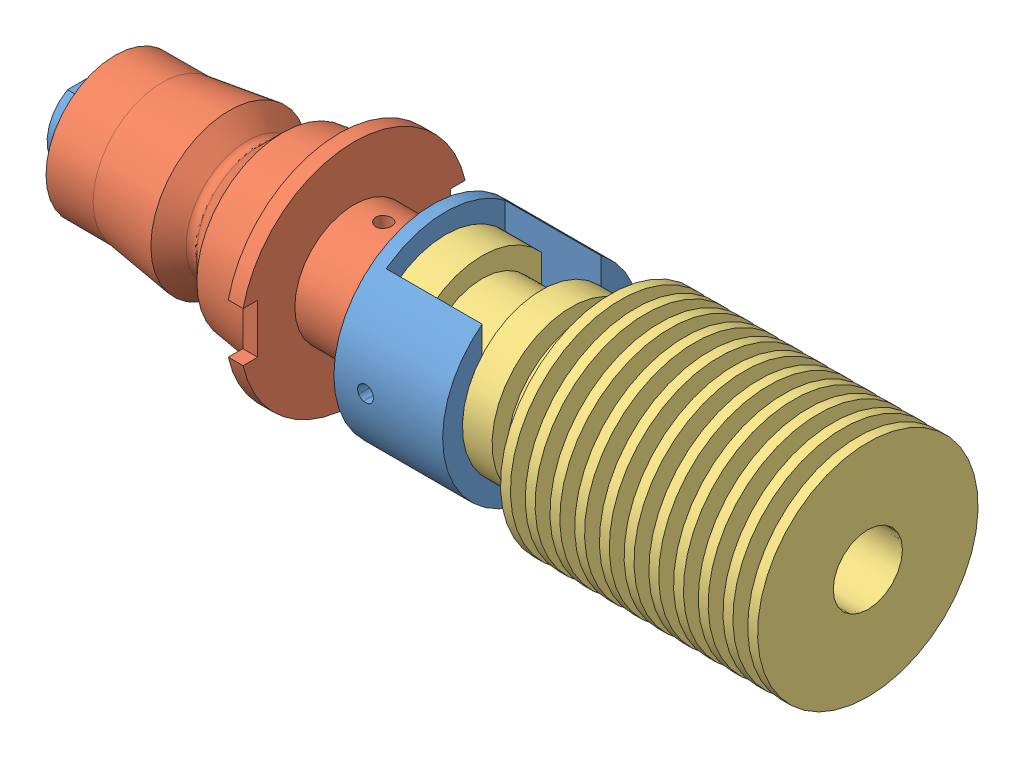
SolidWorks assembly Assem2, configuration Default. Lengths in mm.
Overall size (79 23 22.45).
3 component instances, 3 part files, 5 mates.
Components (placement in the parent):
- adapter_V2-1: adapter_V2 [Default] at (-36.9729 1.0952 22.9875) size (46 20 20)
- ER11 tool holder butt_V2-1: ER11 tool holder butt_V2 [Default] at (-69.101 1.0952 22.9875) size (30.18 23 22.45)
- heatsink-1: heatsink [Default] at (-35.6729 1.0952 22.9875) size (42.7 22.3 22.3)
Mates (geometry in assembly coordinates):
- Concentric1: concentric aligned: circle of adapter_V2-1; cylinder of ER11 tool holder butt_V2-1 through (-38.9245 1.0952 22.9875) axis (-1 0 0) radius 6
- Concentric2: concentric aligned: circle of adapter_V2-1; circle of heatsink-1
- Perpendicular1: perpendicular: plane of heatsink-1 through (7.0281 6.3867 28.9875) normal (0 0 1); line of assembly
- Coincident3: coincident anti-aligned: plane of adapter_V2-1 through (-31.9729 1.0952 22.9875) normal (-1 0 0); plane of heatsink-1 through (-31.9729 -4.9048 22.9875) normal (1 0 0)
- Parallel2: parallel aligned: plane of adapter_V2-1 through (-71.9729 4.5952 21.051) normal (0 1 0); plane of ER11 tool holder butt_V2-1 through (-69.101 -1.4048 34.7375) normal (0 1 0)
